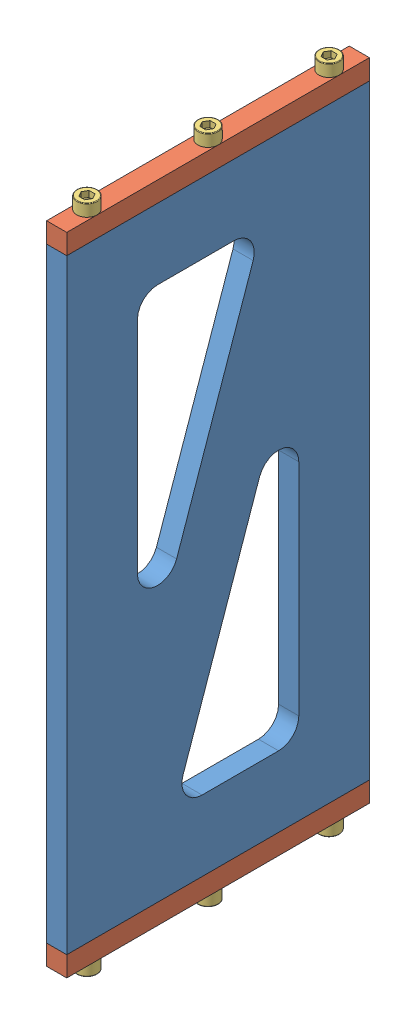
SolidWorks assembly testee, configuration Default. Lengths in mm.
Overall size (10 332 150).
9 component instances, 3 part files, 21 mates.
Components (placement in the parent):
- PLACA B-1: PLACA B [Default] at (16.9679 33.3902 150) x (0 0 -1) z (0 -1 0) size (150 10 300)
- pecinha-1: pecinha [Default] at (16.9679 23.3902 150) x (0 0 -1) z (1 0 0) size (150 10 10)
- socket head cap screw_iso-1: socket head cap screw_iso [ISO 4762 M6 x 20 - 20N] at (21.9679 17.3902 15) x (0 1 0) z (0 0 -1) size (26 10 10)
- socket head cap screw_iso-2: socket head cap screw_iso [ISO 4762 M6 x 20 - 20N] at (21.9679 17.3902 75) x (0 1 0) z (0 0 -1) size (26 10 10)
- socket head cap screw_iso-3: socket head cap screw_iso [ISO 4762 M6 x 20 - 20N] at (21.9679 17.3902 135) x (0 1 0) z (0 0 -1) size (26 10 10)
- pecinha-2: pecinha [Default] at (26.9679 343.3902 150) x (0 0 -1) z (-1 0 0) size (150 10 10)
- socket head cap screw_iso-5: socket head cap screw_iso [ISO 4762 M6 x 20 - 20N] at (21.9679 349.3902 75) x (0 -1 0) z (0 0 1) size (26 10 10)
- socket head cap screw_iso-6: socket head cap screw_iso [ISO 4762 M6 x 20 - 20N] at (21.9679 349.3902 135) x (0 -1 0) z (0 0 1) size (26 10 10)
- socket head cap screw_iso-7: socket head cap screw_iso [ISO 4762 M6 x 20 - 20N] at (21.9679 349.3902 15) x (0 -1 0) z (0 0 1) size (26 10 10)
Mates (geometry in assembly coordinates):
- Coincident1: coincident anti-aligned: plane of PLACA B-1 through (26.9679 33.3902 150) normal (0 -1 0); plane of pecinha-1 through (16.9679 33.3902 150) normal (0 1 0)
- Coincident2: coincident aligned: plane of PLACA B-1 through (26.9679 33.3902 150) normal (1 0 0); plane of pecinha-1 through (26.9679 33.3902 150) normal (1 0 0)
- Coincident3: coincident aligned: plane of PLACA B-1 through (26.9679 33.3902 0) normal (0 0 -1); plane of pecinha-1 through (16.9679 33.3902 0) normal (0 0 -1)
- Concentric1: concentric anti-aligned: cylinder of pecinha-1 through (21.9679 23.3902 15) axis (0 1 0) radius 3.5; cylinder of socket head cap screw_iso-1 through (21.9679 -14.3598 15) axis (0 -1 0) radius 5
- Coincident4: coincident anti-aligned: plane of pecinha-1 through (16.9679 23.3902 150) normal (0 -1 0); plane of socket head cap screw_iso-1 through (26.9679 23.3902 15) normal (0 1 0)
- Concentric2: concentric anti-aligned: cylinder of pecinha-1 through (21.9679 23.3902 75) axis (0 1 0) radius 3.5; cylinder of socket head cap screw_iso-2 through (21.9679 -14.3598 75) axis (0 -1 0) radius 5
- Coincident5: coincident anti-aligned: plane of pecinha-1 through (16.9679 23.3902 150) normal (0 -1 0); plane of socket head cap screw_iso-2 through (26.9679 23.3902 75) normal (0 1 0)
- Concentric3: concentric anti-aligned: cylinder of pecinha-1 through (21.9679 23.3902 135) axis (0 1 0) radius 3.5; cylinder of socket head cap screw_iso-3 through (21.9679 -14.3598 135) axis (0 -1 0) radius 5
- Coincident6: coincident anti-aligned: plane of pecinha-1 through (16.9679 23.3902 150) normal (0 -1 0); plane of socket head cap screw_iso-3 through (26.9679 23.3902 135) normal (0 1 0)
- Coincident7: coincident aligned: plane of PLACA B-1 through (26.9679 33.3902 150) normal (1 0 0); plane of pecinha-2 through (26.9679 333.3902 150) normal (1 0 0)
- Coincident8: coincident aligned: plane of PLACA B-1 through (26.9679 33.3902 0) normal (0 0 -1); plane of pecinha-2 through (26.9679 333.3902 0) normal (0 0 -1)
- Coincident9: coincident anti-aligned: plane of PLACA B-1 through (26.9679 333.3902 150) normal (0 1 0); plane of pecinha-2 through (26.9679 333.3902 150) normal (0 -1 0)
- Concentric4: concentric aligned: cylinder of PLACA B-1 through (135 5 -300) axis (0 0 -1) radius 2.5; cylinder of ? through (135 5 -337.75) axis (0 0 -1) radius 5
- Coincident10: coincident anti-aligned: plane of PLACA B-1; plane of ? through (135 10 -300) normal (0 0 1)
- Concentric5: concentric anti-aligned: cylinder of pecinha-2 through (21.9679 343.3902 75) axis (0 -1 0) radius 3.5; cylinder of socket head cap screw_iso-5 through (21.9679 381.1402 75) axis (0 1 0) radius 5
- Coincident11: coincident anti-aligned: plane of pecinha-2 through (26.9679 343.3902 150) normal (0 1 0); plane of socket head cap screw_iso-5 through (26.9679 343.3902 75) normal (0 -1 0)
- Concentric6: concentric anti-aligned: cylinder of pecinha-2 through (21.9679 343.3902 135) axis (0 -1 0) radius 3.5; cylinder of socket head cap screw_iso-6 through (21.9679 381.1402 135) axis (0 1 0) radius 5
- Coincident12: coincident anti-aligned: plane of pecinha-2 through (26.9679 343.3902 150) normal (0 1 0); plane of socket head cap screw_iso-6 through (26.9679 343.3902 135) normal (0 -1 0)
- Concentric7: concentric anti-aligned: cylinder of pecinha-2 through (21.9679 343.3902 15) axis (0 -1 0) radius 3.5; cylinder of socket head cap screw_iso-7 through (21.9679 381.1402 15) axis (0 1 0) radius 5
- Coincident13: coincident anti-aligned: plane of pecinha-2 through (26.9679 343.3902 150) normal (0 1 0); plane of socket head cap screw_iso-7 through (26.9679 343.3902 15) normal (0 -1 0)
- Coincident19: coincident anti-aligned: plane of PLACA B-1 through (26.9679 33.3902 0) normal (0 0 -1); plane of assembly through (0 0 0) normal (0 0 1)
